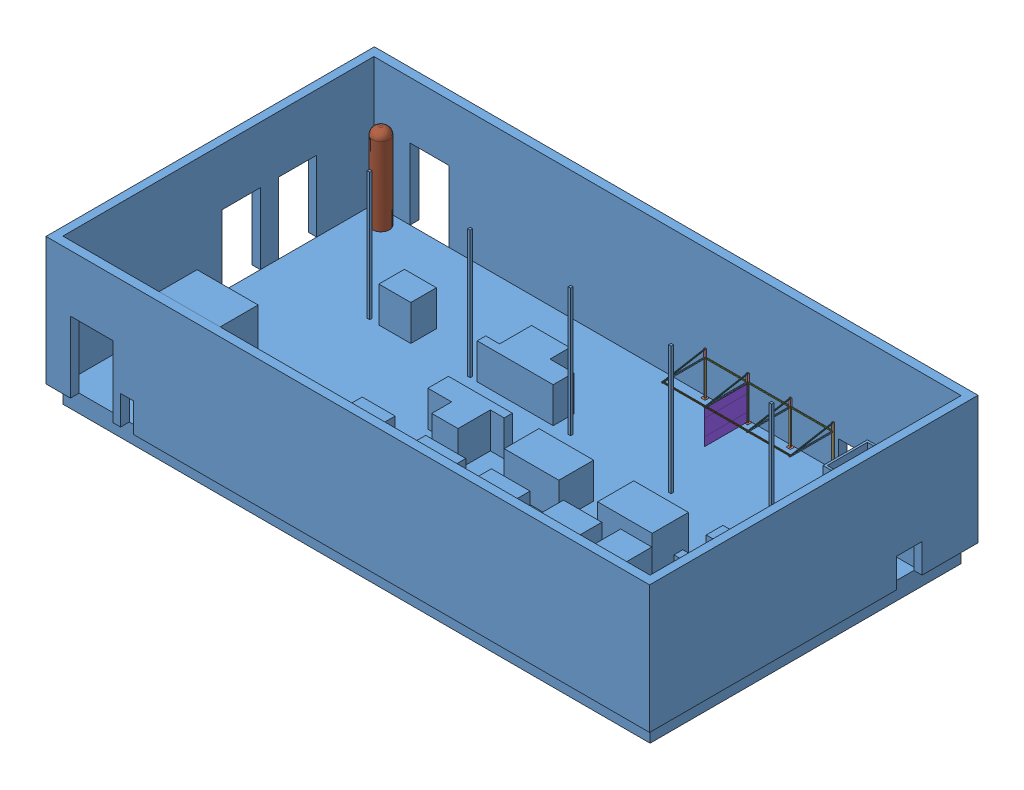
SolidWorks assembly 1410 80th ST SW Unit F, configuration Default. Lengths in mm.
Overall size (43180 10414 23495).
60 component instances, 11 part files, 4 mates.
Components (placement in the parent):
- 1410 80th ST SW Unit F-1: 1410 80th ST SW Unit F [Default] at origin size (43180 10414 23495)
- welding area-1: welding area [Default] at (5892.8089 0 -10972.8) x (0 0 1) z (-1 0 0) size (3257.55 3054.35 9448.8)
  - upright assy-1: upright assy [Default] at origin size (304.8 3054.35 304.8)
    - base plate-1: base plate [Default] at origin size (304.8 6.35 304.8)
    - upright-1: upright [Default] at (0 1530.35 0) size (101.6 3048 101.6)
  - upright assy-2: upright assy [Default] at (0 0 3048) size (304.8 3054.35 304.8)
    - base plate-1: base plate [Default] at origin size (304.8 6.35 304.8)
    - upright-1: upright [Default] at (0 1530.35 0) size (101.6 3048 101.6)
  - upright assy-3: upright assy [Default] at (0 0 -3048) size (304.8 3054.35 304.8)
    - base plate-1: base plate [Default] at origin size (304.8 6.35 304.8)
    - upright-1: upright [Default] at (0 1530.35 0) size (101.6 3048 101.6)
  - upright assy-4: upright assy [Default] at (0 0 -6096) size (304.8 3054.35 304.8)
    - base plate-1: base plate [Default] at origin size (304.8 6.35 304.8)
    - upright-1: upright [Default] at (0 1530.35 0) size (101.6 3048 101.6)
  - curtain arm assy-1: curtain arm assy [Default] at (50.8 2749.55 -3048) x (0 0 -1) z (1 0 0) size (101.6 609.6 3056.82)
    - tube mount-1: tube mount [Default] at origin size (101.6 609.6 6.35)
    - curtain arm main-1: curtain arm main [Default] at (0 -254 1530.35) size (50.8 76.2 3048)
    - gusset tube-1: gusset tube [Default] at (0 2.4461 1502.7864) x (1 0 0) z (0 -0.173648 0.984808) size (50.8 50.8 2925.46)
  - curtain arm assy-2: curtain arm assy [Default] at (50.8 2749.55 0) x (0 0 -1) z (1 0 0) size (101.6 609.6 3056.82)
    - tube mount-1: tube mount [Default] at origin size (101.6 609.6 6.35)
    - curtain arm main-1: curtain arm main [Default] at (0 -254 1530.35) size (50.8 76.2 3048)
    - gusset tube-1: gusset tube [Default] at (0 2.4461 1502.7864) x (1 0 0) z (0 -0.173648 0.984808) size (50.8 50.8 2925.46)
  - curtain arm assy-3: curtain arm assy [Default] at (50.8 2749.55 3048) x (0 0 -1) z (1 0 0) size (101.6 609.6 3056.82)
    - tube mount-1: tube mount [Default] at origin size (101.6 609.6 6.35)
    - curtain arm main-1: curtain arm main [Default] at (0 -254 1530.35) size (50.8 76.2 3048)
    - gusset tube-1: gusset tube [Default] at (0 2.4461 1502.7864) x (1 0 0) z (0 -0.173648 0.984808) size (50.8 50.8 2925.46)
  - curtain arm assy-4: curtain arm assy [Default] at (50.8 2749.55 -6096) x (0 0 -1) z (1 0 0) size (101.6 609.6 3056.82)
    - tube mount-1: tube mount [Default] at origin size (101.6 609.6 6.35)
    - curtain arm main-1: curtain arm main [Default] at (0 -254 1530.35) size (50.8 76.2 3048)
    - gusset tube-1: gusset tube [Default] at (0 2.4461 1502.7864) x (1 0 0) z (0 -0.173648 0.984808) size (50.8 50.8 2925.46)
  - cross bar assy-1: cross bar assy [Default] at (0 2495.55 1524) size (101.6 609.6 2946.4)
    - cross bar-1: cross bar [Default] at origin size (50.8 76.2 2933.7)
    - tube mount-1: tube mount [Default] at (0 254 1466.85) size (101.6 609.6 6.35)
    - tube mount-2: tube mount [Default] at (0 254 -1473.2) size (101.6 609.6 6.35)
  - cross bar assy-3: cross bar assy [Default] at (0 2495.55 -1524) size (101.6 609.6 2946.4)
    - cross bar-1: cross bar [Default] at origin size (50.8 76.2 2933.7)
    - tube mount-1: tube mount [Default] at (0 254 1466.85) size (101.6 609.6 6.35)
    - tube mount-2: tube mount [Default] at (0 254 -1473.2) size (101.6 609.6 6.35)
  - cross bar assy-4: cross bar assy [Default] at (0 2495.55 -4572) size (101.6 609.6 2946.4)
    - cross bar-1: cross bar [Default] at origin size (50.8 76.2 2933.7)
    - tube mount-1: tube mount [Default] at (0 254 1466.85) size (101.6 609.6 6.35)
    - tube mount-2: tube mount [Default] at (0 254 -1473.2) size (101.6 609.6 6.35)
  - curtain-1: curtain [Default] at (1581.15 349.25 0) x (0 0 -1) z (1 0 0) size (3.17 2362.2 3048) (hidden)
  - curtain-2: curtain [Default] at (1581.15 349.25 3048) x (0 0 1) z (-1 0 0) size (3.17 2362.2 3048) (hidden)
  - curtain-3: curtain [Default] at (1581.15 349.25 -3048) x (0 0 1) z (-1 0 0) size (3.17 2362.2 3048) (hidden)
  - curtain-4: curtain [Default] at (1581.15 349.25 -6096) x (0 0 1) z (-1 0 0) size (3.17 2362.2 3048) (hidden)
  - front cross bar-1: front cross bar [Default] at (3028.95 2495.55 -4572) size (152.4 76.2 2997.2)
    - outer cross bar-1: outer cross bar [Default] at origin size (50.8 76.2 2984.5)
    - front cross mount-1: front cross mount [Default] at (0 0 1492.25) x (0 1 0) z (0 0 1) size (76.2 152.4 6.35)
    - front cross mount-2: front cross mount [Default] at (0 0 -1498.6) x (0 -1 0) z (0 0 1) size (76.2 152.4 6.35)
  - curtain-5: curtain [Default] at (3028.95 349.25 -4562.4829) x (-1 0 0) z (0 0 -1) size (3.17 2362.2 3048) (hidden)
  - front cross bar-2: front cross bar [Default] at (3028.95 2495.55 -1524) size (152.4 76.2 2997.2)
    - outer cross bar-1: outer cross bar [Default] at origin size (50.8 76.2 2984.5)
    - front cross mount-1: front cross mount [Default] at (0 0 1492.25) x (0 1 0) z (0 0 1) size (76.2 152.4 6.35)
    - front cross mount-2: front cross mount [Default] at (0 0 -1498.6) x (0 -1 0) z (0 0 1) size (76.2 152.4 6.35)
  - front cross bar-3: front cross bar [Default] at (3028.95 2495.55 1524) size (152.4 76.2 2997.2)
    - outer cross bar-1: outer cross bar [Default] at origin size (50.8 76.2 2984.5)
    - front cross mount-1: front cross mount [Default] at (0 0 1492.25) x (0 1 0) z (0 0 1) size (76.2 152.4 6.35)
    - front cross mount-2: front cross mount [Default] at (0 0 -1498.6) x (0 -1 0) z (0 0 1) size (76.2 152.4 6.35)
- Air Tank-1: Air Tank [Default] at (-19458.1842 0 -10084.4471) size (1219.2 6096 1219.2)
Mates (geometry in assembly coordinates):
- Coincident1: coincident anti-aligned: plane of 1410 80th ST SW Unit F-1 through (0 0 0) normal (0 1 0); plane of welding area-1/upright assy-4/base plate-1 through (11849.1089 0 -11112.5) normal (0 -1 0)
- Coincident2: coincident aligned: line of 1410 80th ST SW Unit F-1 through (14300.2 0 -11125.2) axis (-1 0 0); line of welding area-1/upright assy-4/base plate-1 through (12128.5089 0 -11125.2) axis (-1 0 0)
- Distance1: distance = 2260.6 mm: line of welding area-1/upright assy-4/upright-1 through (12039.6089 6.35 -10928.35) axis (0 0 -1); line of 1410 80th ST SW Unit F-1 through (14300.2 0 -11125.2) axis (0 0 1)
- Coincident3: coincident anti-aligned: plane of 1410 80th ST SW Unit F-1 through (0 0 0) normal (0 1 0); plane of Air Tank-1 through (-19458.1842 0 -10084.4471) normal (0 -1 0)
